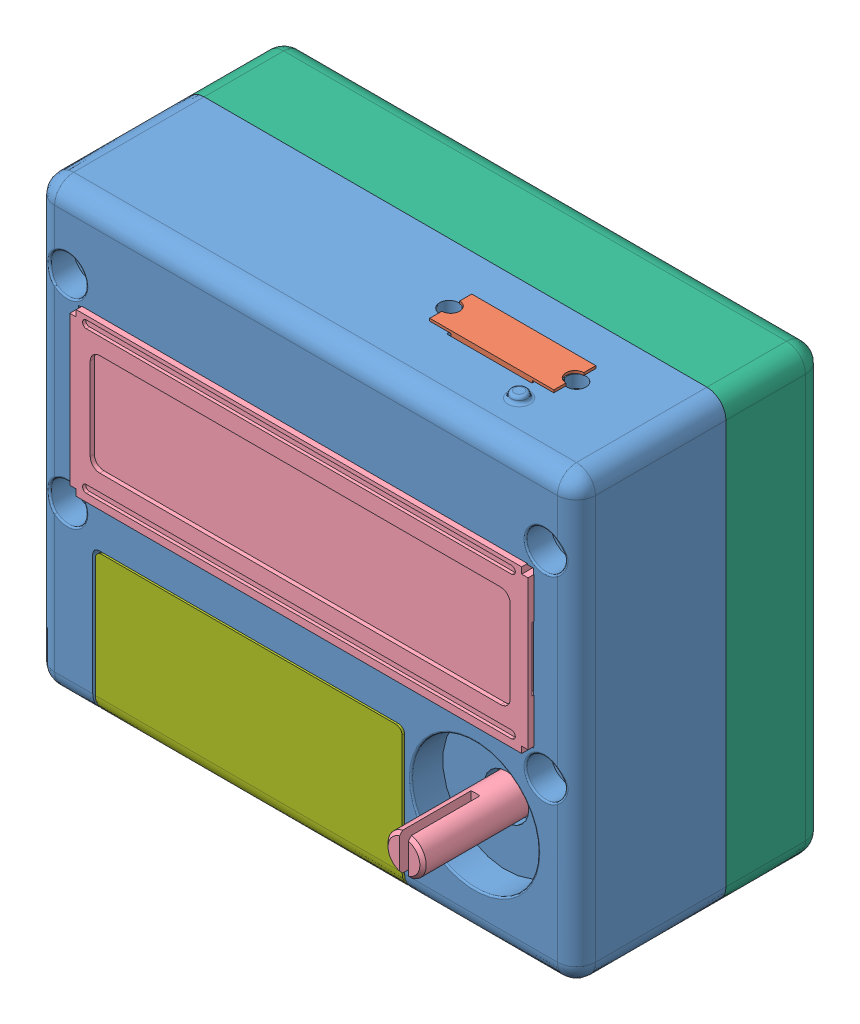
SolidWorks assembly Assemblage1, configuration Défaut. Lengths in mm.
Overall size (85 70.5 50.1).
12 component instances, 7 part files, 27 mates.
Components (placement in the parent):
- half_top-1: half_top [Défaut] at (-55.4059 39.8957 102) size (85 70.5 23.5)
- slide_switch-1: slide_switch [Défaut] at (-0.8059 39.8957 93.3) x (0 0 1) z (0 -1 0) size (23.97 19.5 6)
- bat_500mah-1: bat_500mah [Défaut] at (-41.4059 -6.6043 91) size (48.5 22 9)
- margoulineur2000RevB-1: margoulineur2000RevB [Défaut] at (-52.9059 39.3957 82.875) size (81.34 64.5 46.05)
- standoff FF M3x11-1: standoff FF M3x11 [Défaut] at (24.5941 28.3957 83.47) x (0.990086 0.140459 0) z (0 0 1) size (5 5.77 11)
- standoff FF M3x11-2: standoff FF M3x11 [Défaut] at (-50.4059 28.3957 83.47) x (0.924494 0.381196 0) z (0 0 1) size (5 5.77 11)
- standoff FF M3x11-3: standoff FF M3x11 [Défaut] at (-50.4059 -2.6043 83.47) x (-0.311475 0.950254 0) z (0 0 1) size (5 5.77 11)
- standoff FF M3x11-4: standoff FF M3x11 [Défaut] at (24.5941 -2.6043 83.47) x (0.267878 -0.963453 0) z (0 0 1) size (5 5.77 11)
- standoff FF M3x11-5: standoff FF M3x11 [Défaut] at (1.1581 18.3957 71.25) x (0.340053 0.940406 0) z (0 0 1) size (5 5.77 11)
- standoff FF M3x11-6: standoff FF M3x11 [Défaut] at (-26.8419 -6.6043 71.25) x (0.529869 0.84808 0) z (0 0 1) size (5 5.77 11)
- half_bot-1: half_bot [Défaut] at (-55.4059 -29.6043 67) x (1 0 0) z (0 0 -1) size (85 69.5 17)
- bat trap-1: bat trap [Défaut] at (2.1941 -29.6043 104) x (-1 0 0) z (0 0 -1) size (48.2 26.8 21.3)
Mates (geometry in assembly coordinates):
- Coïncidente25: coincident aligned: plane of half_top-1 through (29.5941 39.8957 96.1) normal (0 0 -1); plane of margoulineur2000RevB-1 through (-12.9059 12.8957 96.1) normal (0 0 -1)
- Coaxiale4: concentric aligned: cylinder of half_top-1 through (-50.4059 28.3957 100) axis (0 0 1) radius 1.75; cylinder of margoulineur2000RevB-1 through (-50.4059 28.3957 94.5) axis (0 0 1) radius 1.25
- Coaxiale6: concentric aligned: cylinder of half_top-1 through (24.5941 -2.6043 100) axis (0 0 1) radius 1.75; cylinder of margoulineur2000RevB-1 through (24.5941 -2.6043 94.5) axis (0 0 1) radius 1.25
- Coaxiale7: concentric aligned: cylinder of margoulineur2000RevB-1 through (-50.4059 28.3957 82.25) axis (0 0 -1) radius 1.6; cylinder of standoff FF M3x11-2 through (-50.4059 28.3957 94.47) axis (0 0 -1) radius 1.5
- Coaxiale8: concentric aligned: cylinder of margoulineur2000RevB-1 through (24.5941 28.3957 82.25) axis (0 0 -1) radius 1.6; cylinder of standoff FF M3x11-1 through (24.5941 28.3957 94.47) axis (0 0 -1) radius 1.5
- Coaxiale9: concentric aligned: cylinder of margoulineur2000RevB-1 through (24.5941 -2.6043 82.25) axis (0 0 -1) radius 1.6; cylinder of standoff FF M3x11-4 through (24.5941 -2.6043 94.47) axis (0 0 -1) radius 1.5
- Coaxiale10: concentric aligned: cylinder of margoulineur2000RevB-1 through (-50.4059 -2.6043 82.25) axis (0 0 -1) radius 1.6; cylinder of standoff FF M3x11-3 through (-50.4059 -2.6043 94.47) axis (0 0 -1) radius 1.5
- Coïncidente26: coincident aligned: plane of margoulineur2000RevB-1 through (-50.4059 -2.6043 94.47) normal (0 0 1); plane of standoff FF M3x11-3 through (-50.4059 -2.6043 94.47) normal (0 0 1)
- Coïncidente28: coincident aligned: plane of margoulineur2000RevB-1 through (-50.4059 28.3957 94.47) normal (0 0 1); circle of standoff FF M3x11-2
- Coïncidente29: coincident aligned: plane of margoulineur2000RevB-1 through (24.5941 28.3957 94.47) normal (0 0 1); plane of standoff FF M3x11-1 through (24.5941 28.3957 94.47) normal (0 0 1)
- Coïncidente30: coincident aligned: plane of margoulineur2000RevB-1 through (24.5941 -2.6043 94.47) normal (0 0 1); plane of standoff FF M3x11-4 through (24.5941 -2.6043 94.47) normal (0 0 1)
- Coaxiale11: concentric aligned: cylinder of margoulineur2000RevB-1 through (1.1581 18.3957 82.25) axis (0 0 -1) radius 1.6; cylinder of standoff FF M3x11-5 through (1.1581 18.3957 82.25) axis (0 0 -1) radius 1.5
- Coaxiale12: concentric aligned: cylinder of margoulineur2000RevB-1 through (-26.8419 -6.6043 82.25) axis (0 0 -1) radius 1.6; cylinder of standoff FF M3x11-6 through (-26.8419 -6.6043 82.25) axis (0 0 -1) radius 1.5
- Coïncidente31: coincident anti-aligned: plane of margoulineur2000RevB-1 through (21.0941 37.3957 82.25) normal (0 0 -1); plane of standoff FF M3x11-6 through (-26.8419 -6.6043 82.25) normal (0 0 1)
- Coïncidente32: coincident anti-aligned: plane of margoulineur2000RevB-1 through (21.0941 37.3957 82.25) normal (0 0 -1); plane of standoff FF M3x11-5 through (1.1581 18.3957 82.25) normal (0 0 1)
- Coaxiale13: concentric anti-aligned: cylinder of half_top-1 through (-50.9059 -25.1043 92) axis (0 0 -1) radius 1.75; cylinder of half_bot-1 through (-50.9059 -25.1043 59) axis (0 0 1) radius 1.75
- Coaxiale14: concentric anti-aligned: cylinder of half_top-1 through (25.0941 35.3957 92) axis (0 0 -1) radius 1.75; cylinder of half_bot-1 through (25.0941 35.3957 59) axis (0 0 1) radius 1.75
- Coïncidente33: coincident anti-aligned: plane of half_top-1 through (-55.4059 39.8957 82) normal (0 0 -1); plane of half_bot-1 through (-55.4059 -29.6043 82) normal (0 0 1)
- Coïncidente34: coincident anti-aligned: plane of half_top-1 through (-55.4059 39.8957 104) normal (0 1 0); plane of slide_switch-1 through (-0.8059 39.8957 93.3) normal (0 -1 0)
- Coïncidente39: coincident anti-aligned: plane of half_top-1 through (-55.4059 39.8957 91) normal (0 0 1); plane of bat_500mah-1 through (-41.4059 -6.6043 91) normal (0 0 -1)
- Coïncidente40: coincident anti-aligned: plane of half_top-1 through (2.5941 -6.6043 91) normal (-1 0 0); plane of bat_500mah-1 through (2.5941 -6.6043 100) normal (1 0 0)
- Coïncidente41: coincident anti-aligned: plane of half_top-1 through (-46.4059 -6.6043 91) normal (0 -1 0); plane of bat_500mah-1 through (-41.4059 -6.6043 100) normal (0 1 0)
- Coïncidente43: coincident aligned: plane of half_top-1 through (-55.4059 -29.6043 104) normal (0 -1 0); plane of bat trap-1 through (2.1941 -29.6043 102) normal (0 -1 0)
- Coïncidente44: coincident aligned: plane of half_top-1 through (-55.4059 39.8957 104) normal (0 0 1); plane of bat trap-1 through (2.1941 -29.6043 104) normal (0 0 1)
- Distance1: distance = 0.4 mm anti-aligned: plane of bat trap-1 through (-46.0059 -29.6043 102) normal (-1 0 0); plane of half_top-1 through (-46.4059 -6.6043 91) normal (1 0 0)
- Coïncidente53: coincident: point of half_top-1; point of slide_switch-1
- Parallèle4: parallel anti-aligned: plane of half_top-1 through (-1.1059 31.8957 86.3) normal (0 0 1); plane of slide_switch-1 through (-0.8059 34.2957 86.7) normal (0 0 -1)
